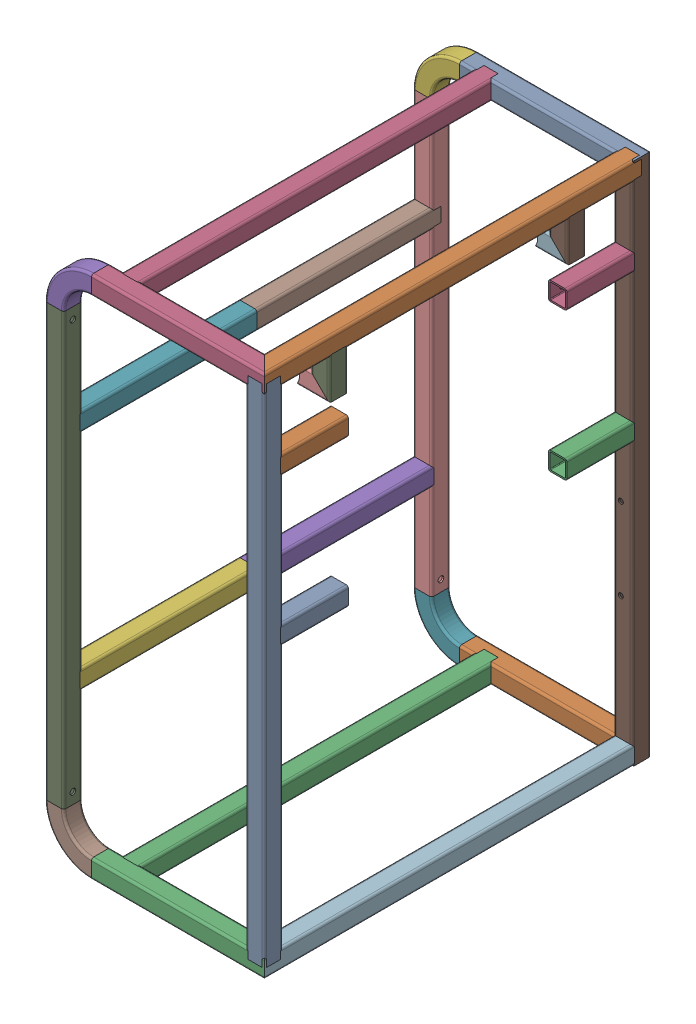
SolidWorks assembly Frame0002.stp, configuration Default. Lengths in mm.
Overall size (295 705 520).
28 component instances, 28 part files, 0 mates.
Components (placement in the parent):
- DIN 25 x 25 x 2 00000021.stp-1: DIN 25 x 25 x 2 00000021.stp [Default] at (-133.3987 317.2186 -247.5) x (0 0 -1) z (1 0 0) size (25 25 232.5)
- DIN 25 x 25 x 2 00000022.stp-1: DIN 25 x 25 x 2 00000022.stp [Default] at (-133.3987 -362.7814 -247.5) x (0 0 -1) z (1 0 0) size (25 25 232.5)
- DIN 25 x 25 x 2 00000023.stp-1: DIN 25 x 25 x 2 00000023.stp [Default] at (-133.3987 -362.7814 247.5) x (0 0 -1) z (1 0 0) size (25 25 232.5)
- DIN 25 x 25 x 2 00000024.stp-1: DIN 25 x 25 x 2 00000024.stp [Default] at (-133.3987 317.2186 247.5) x (0 0 -1) z (1 0 0) size (25 25 232.5)
- DIN 25 x 25 x 2 00000025.stp-1: DIN 25 x 25 x 2 00000025.stp [Default] at (-183.3987 267.2186 247.5) x (0 0 -1) z (0 1 0) size (25 62.5 62.5)
- DIN 25 x 25 x 2 00000026.stp-1: DIN 25 x 25 x 2 00000026.stp [Default] at (-183.3987 267.2186 -247.5) x (0 0 -1) z (0 1 0) size (25 62.5 62.5)
- DIN 25 x 25 x 2 00000027.stp-1: DIN 25 x 25 x 2 00000027.stp [Default] at (-183.3987 -312.7814 -247.5) x (0 0 -1) z (0 -1 0) size (25 62.5 62.5)
- DIN 25 x 25 x 2 00000028.stp-1: DIN 25 x 25 x 2 00000028.stp [Default] at (-183.3987 -312.7814 247.5) x (0 0 -1) z (0 -1 0) size (25 62.5 62.5)
- DIN 25 x 25 x 2 00000029.stp-1: DIN 25 x 25 x 2 00000029.stp [Default] at (-183.3987 267.2186 247.5) x (0 0 -1) z (0 -1 0) size (25 25 580)
- DIN 25 x 25 x 2 00000030.stp-1: DIN 25 x 25 x 2 00000030.stp [Default] at (-183.3987 267.2186 -247.5) x (0 0 -1) z (0 -1 0) size (25 25 580)
- DIN 25 x 25 x 2 00000031.stp-1: DIN 25 x 25 x 2 00000031.stp [Default] at (86.6013 -362.7814 -247.5) x (0 0 -1) z (0 1 0) size (25 25 705)
- DIN 25 x 25 x 2 00000032.stp-1: DIN 25 x 25 x 2 00000032.stp [Default] at (86.6013 -362.7814 247.5) x (0 -1 0) z (0 0 -1) size (25 25 507.5)
- DIN 25 x 25 x 2 00000033.stp-1: DIN 25 x 25 x 2 00000033.stp [Default] at (86.6013 317.2186 247.5) x (0 0 1) z (0 -1 0) size (25 25 680)
- DIN 25 x 25 x 2 00000034.stp-1: DIN 25 x 25 x 2 00000034.stp [Default] at (86.6013 317.2186 -247.5) x (0 1 0) z (0 0 1) size (25 25 507.5)
- DIN 25 x 25 x 2 00000035.stp-1: DIN 25 x 25 x 2 00000035.stp [Default] at (-103.3987 -362.7814 -247.5) size (25 25 495)
- DIN 25 x 25 x 2 00000036.stp-1: DIN 25 x 25 x 2 00000036.stp [Default] at (-103.3987 317.2186 -247.5) size (25 25 495)
- DIN 25 x 25 x 2 00000037.stp-1: DIN 25 x 25 x 2 00000037.stp [Default] at (-183.3987 -172.7814 -247.5) x (0 -1 0) z (0 0 1) size (25 25 247.5)
- DIN 25 x 25 x 2 00000038.stp-1: DIN 25 x 25 x 2 00000038.stp [Default] at (-183.3987 -172.7814 0) x (0 -1 0) z (0 0 1) size (25 25 247.5)
- DIN 25 x 25 x 2 00000039.stp-1: DIN 25 x 25 x 2 00000039.stp [Default] at (-183.3987 127.2186 0) x (0 -1 0) z (0 0 1) size (25 25 247.5)
- DIN 25 x 25 x 2 00000040.stp-1: DIN 25 x 25 x 2 00000040.stp [Default] at (-183.3987 127.2186 -247.5) x (0 -1 0) z (0 0 1) size (25 25 247.5)
- DIN 25 x 25 x 2 00000041.stp-1: DIN 25 x 25 x 2 00000041.stp [Default] at (86.6013 317.2186 160.145) x (-1 0 0) z (0 -1 0) size (25 25 65)
- DIN 25 x 25 x 2 00000042.stp-1: DIN 25 x 25 x 2 00000042.stp [Default] at (86.6013 264.7186 160.145) x (0 1 0) z (-1 0 0) size (25.02 25.02 44.4)
- DIN 25 x 25 x 2 00000043.stp-1: DIN 25 x 25 x 2 00000043.stp [Default] at (86.6013 317.2186 -160.145) x (-1 0 0) z (0 -1 0) size (25 25 65)
- DIN 25 x 25 x 2 00000044.stp-1: DIN 25 x 25 x 2 00000044.stp [Default] at (86.6013 264.7186 -160.145) x (0 1 0) z (-1 0 0) size (25.02 25.02 44.4)
- DIN 25 x 25 x 2 00000045.stp-1: DIN 25 x 25 x 2 00000045.stp [Default] at (86.6013 14.2186 247.5) x (-1 0 0) z (0 0 -1) size (25 25 100.5)
- DIN 25 x 25 x 2 00000046.stp-1: DIN 25 x 25 x 2 00000046.stp [Default] at (86.6013 212.2186 247.5) x (-1 0 0) z (0 0 -1) size (25 25 100.5)
- DIN 25 x 25 x 2 00000047.stp-1: DIN 25 x 25 x 2 00000047.stp [Default] at (86.6013 14.2186 -247.5) size (25 25 100.5)
- DIN 25 x 25 x 2 00000048.stp-1: DIN 25 x 25 x 2 00000048.stp [Default] at (86.6013 212.2186 -247.5) size (25 25 100.5)
